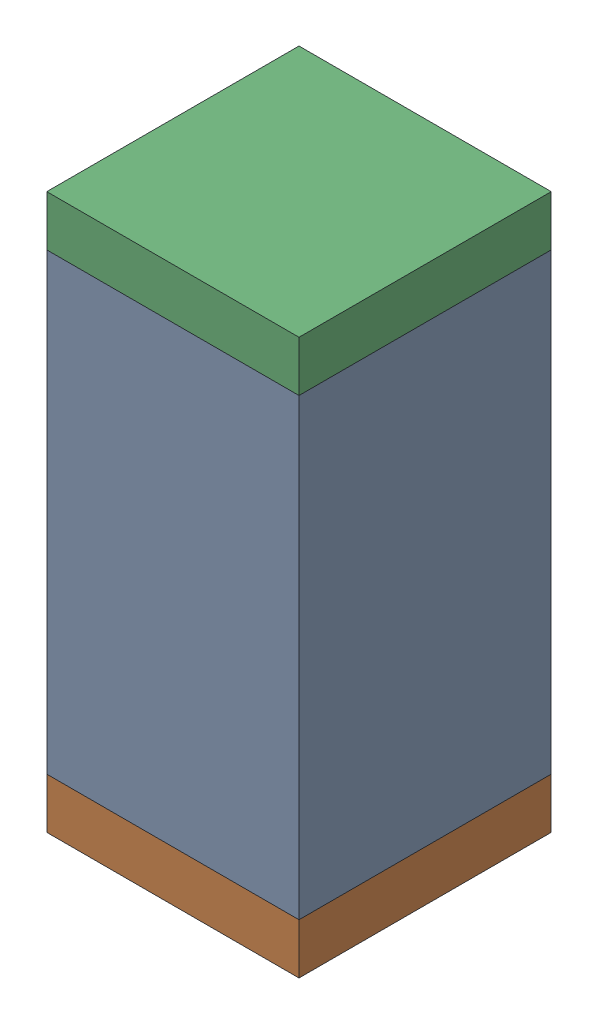
SolidWorks assembly C74, configuration Default. Lengths in mm.
Overall size (0.5 1.1 0.5).
6 component instances, 2 part files, 0 mates.
Components (placement in the parent):
- 791586336-1: 791586336 [Default] at (115.1 59.35 0) size (0.5 0.9 0.5)
  - Extruded_8-1: Extruded_8 [Default] at origin size (0.5 0.9 0.5)
- 810157360-1: 810157360 [Default] at (115.1 58.85 0) size (0.5 0.1 0.5)
  - Extruded_9-1: Extruded_9 [Default] at origin size (0.5 0.1 0.5)
- 810157360-2: 810157360 [Default] at (115.1 59.85 0) size (0.5 0.1 0.5)
  - Extruded_9-1: Extruded_9 [Default] at origin size (0.5 0.1 0.5)
